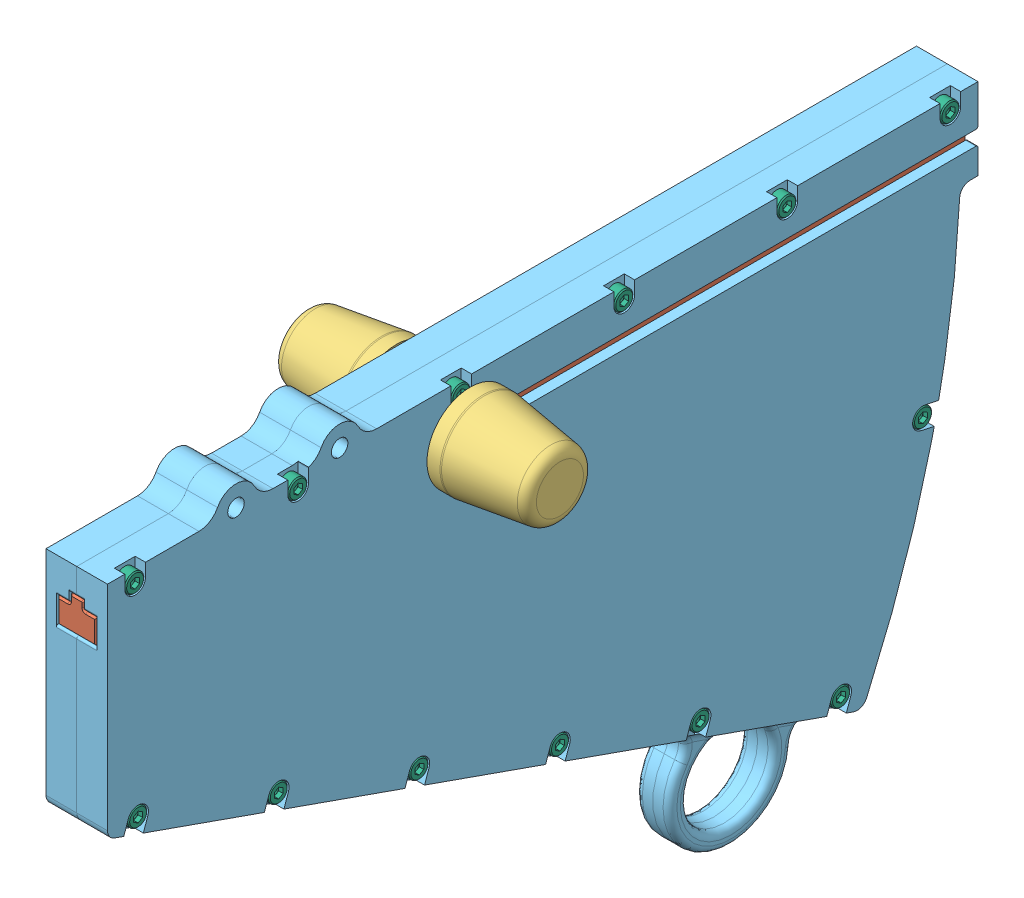
SolidWorks assembly Magazine, configuration Default. Lengths in mm.
Overall size (73.4 166.64 252).
33 component instances, 9 part files, 0 mates.
Components (placement in the parent):
- Follower^Zip Tie Installer-1-1: Follower^Zip Tie Installer-1 [Default] at origin size (14.2 90.09 211.9)
- Pusher Group^Magazine-1: Pusher Group^Magazine [Default] at (0 0 -5.98) size (73.4 25 252) (virtual)
  - Pusher^Zip Tie Installer-1-1: Pusher^Zip Tie Installer-1 [Default] at origin size (11.4 9.7 252)
  - Knob-1-1: Knob-1 [Default] at (10.7 -34.384 -140) x (0 0 -1) z (1 0 0) size (25 25 26)
  - Knob-1-2: Knob-1 [Default] at (-10.7 -34.384 -140) x (0 0 1) z (-1 0 0) size (25 25 26)
  - Dowel Pin 4mm(50mm)-1-1: Dowel Pin 4mm(50mm)-1 [Default] at (0 -34.384 -140) x (0 0 1) z (-1 0 0) size (4 4 50)
- Magazine Casing^Zip Tie Installer-1-1: Magazine Casing^Zip Tie Installer-1 [Default] at origin size (17.8 166.64 252)
- socket head cap screw_am(B18.3.1M - 3 x 0.5 x 10 Hex SHCS -- 10NHX)-1-1: socket head cap screw_am(B18.3.1M - 3 x 0.5 x 10 Hex SHCS -- 10NHX)-1 [Default] at (8.9 -24.334 -239.6) x (-1 0 0) z (0 0 -1) size (13 5.5 5.5)
- socket head cap screw_am(B18.3.1M - 3 x 0.5 x 10 Hex SHCS -- 10NHX)-1-2: socket head cap screw_am(B18.3.1M - 3 x 0.5 x 10 Hex SHCS -- 10NHX)-1 [Default] at (8.9 -24.334 -50.8) x (-1 0 0) z (0 0 -1) size (13 5.5 5.5)
- socket head cap screw_am(B18.3.1M - 3 x 0.5 x 10 Hex SHCS -- 10NHX)-1-3: socket head cap screw_am(B18.3.1M - 3 x 0.5 x 10 Hex SHCS -- 10NHX)-1 [Default] at (8.9 -97.7396 -92.374) x (-1 0 0) z (0 0 -1) size (13 5.5 5.5)
- socket head cap screw_am(B18.3.1M - 3 x 0.5 x 10 Hex SHCS -- 10NHX)-1-4: socket head cap screw_am(B18.3.1M - 3 x 0.5 x 10 Hex SHCS -- 10NHX)-1 [Default] at (8.9 -24.334 -98) x (-1 0 0) z (0 0 -1) size (13 5.5 5.5)
- socket head cap screw_am(B18.3.1M - 3 x 0.5 x 10 Hex SHCS -- 10NHX)-1-5: socket head cap screw_am(B18.3.1M - 3 x 0.5 x 10 Hex SHCS -- 10NHX)-1 [Default] at (8.9 -155.0768 -255.172) x (-1 0 0) z (0 0 -1) size (13 5.5 5.5)
- socket head cap screw_am(B18.3.1M - 3 x 0.5 x 10 Hex SHCS -- 10NHX)-1-6: socket head cap screw_am(B18.3.1M - 3 x 0.5 x 10 Hex SHCS -- 10NHX)-1 [Default] at (8.9 -112.0739 -133.0735) x (-1 0 0) z (0 0 -1) size (13 5.5 5.5)
- socket head cap screw_am(B18.3.1M - 3 x 0.5 x 10 Hex SHCS -- 10NHX)-1-7: socket head cap screw_am(B18.3.1M - 3 x 0.5 x 10 Hex SHCS -- 10NHX)-1 [Default] at (8.9 -24.334 -286.8) x (-1 0 0) z (0 0 -1) size (13 5.5 5.5)
- socket head cap screw_am(B18.3.1M - 3 x 0.5 x 10 Hex SHCS -- 10NHX)-1-8: socket head cap screw_am(B18.3.1M - 3 x 0.5 x 10 Hex SHCS -- 10NHX)-1 [Default] at (8.9 -24.334 -192.4) x (-1 0 0) z (0 0 -1) size (13 5.5 5.5)
- socket head cap screw_am(B18.3.1M - 3 x 0.5 x 10 Hex SHCS -- 10NHX)-1-9: socket head cap screw_am(B18.3.1M - 3 x 0.5 x 10 Hex SHCS -- 10NHX)-1 [Default] at (8.9 -140.7425 -214.4725) x (-1 0 0) z (0 0 -1) size (13 5.5 5.5)
- socket head cap screw_am(B18.3.1M - 3 x 0.5 x 10 Hex SHCS -- 10NHX)-1-10: socket head cap screw_am(B18.3.1M - 3 x 0.5 x 10 Hex SHCS -- 10NHX)-1 [Default] at (8.9 -126.4082 -173.773) x (-1 0 0) z (0 0 -1) size (13 5.5 5.5)
- socket head cap screw_am(B18.3.1M - 3 x 0.5 x 10 Hex SHCS -- 10NHX)-1-11: socket head cap screw_am(B18.3.1M - 3 x 0.5 x 10 Hex SHCS -- 10NHX)-1 [Default] at (8.9 -83.4053 -51.6745) x (-1 0 0) z (0 0 -1) size (13 5.5 5.5)
- socket head cap screw_am(B18.3.1M - 3 x 0.5 x 10 Hex SHCS -- 10NHX)-1-12: socket head cap screw_am(B18.3.1M - 3 x 0.5 x 10 Hex SHCS -- 10NHX)-1 [Default] at (8.9 -24.334 -145.2) x (-1 0 0) z (0 0 -1) size (13 5.5 5.5)
- socket head cap screw_am(B18.3.1M - 3 x 0.5 x 10 Hex SHCS -- 10NHX)-1-13: socket head cap screw_am(B18.3.1M - 3 x 0.5 x 10 Hex SHCS -- 10NHX)-1 [Default] at (8.9 -96.9035 -278.8752) x (-1 0 0) z (0 0 -1) size (13 5.5 5.5)
- Compression Spring 10mm-1-1: Compression Spring 10mm-1 [Default] at (0 -56.02 -53.984) size (6.82 12.35 6.82)
- Rectangular Spring-1-1: Rectangular Spring-1 [Default] at (0 -101.0153 -160.6758) x (0 -0.332197 -0.94321) z (-1 0 0) size (180.85 16.04 8.85)
- 94180A331_HEAT-SET INSERTS FOR PLASTICS-1-1: 94180A331_HEAT-SET INSERTS FOR PLASTICS-1 [Default] at (0 -96.9035 -278.8752) x (0 -1 0) z (0 0 1) size (5.56 4.12 5.56)
- 94180A331_HEAT-SET INSERTS FOR PLASTICS-1-2: 94180A331_HEAT-SET INSERTS FOR PLASTICS-1 [Default] at (0 -24.334 -98) x (0 -1 0) z (0 0 1) size (5.56 4.12 5.56)
- 94180A331_HEAT-SET INSERTS FOR PLASTICS-1-3: 94180A331_HEAT-SET INSERTS FOR PLASTICS-1 [Default] at (0 -24.334 -286.8) x (0 -1 0) z (0 0 1) size (5.56 4.12 5.56)
- 94180A331_HEAT-SET INSERTS FOR PLASTICS-1-4: 94180A331_HEAT-SET INSERTS FOR PLASTICS-1 [Default] at (0 -24.334 -145.2) x (0 -1 0) z (0 0 1) size (5.56 4.12 5.56)
- 94180A331_HEAT-SET INSERTS FOR PLASTICS-1-5: 94180A331_HEAT-SET INSERTS FOR PLASTICS-1 [Default] at (0 -126.4082 -173.773) x (0 -1 0) z (0 0 1) size (5.56 4.12 5.56)
- 94180A331_HEAT-SET INSERTS FOR PLASTICS-1-6: 94180A331_HEAT-SET INSERTS FOR PLASTICS-1 [Default] at (0 -97.7396 -92.374) x (0 -1 0) z (0 0 1) size (5.56 4.12 5.56)
- 94180A331_HEAT-SET INSERTS FOR PLASTICS-1-7: 94180A331_HEAT-SET INSERTS FOR PLASTICS-1 [Default] at (0 -24.334 -239.6) x (0 -1 0) z (0 0 1) size (5.56 4.12 5.56)
- 94180A331_HEAT-SET INSERTS FOR PLASTICS-1-8: 94180A331_HEAT-SET INSERTS FOR PLASTICS-1 [Default] at (0 -140.7425 -214.4725) x (0 -1 0) z (0 0 1) size (5.56 4.12 5.56)
- 94180A331_HEAT-SET INSERTS FOR PLASTICS-1-9: 94180A331_HEAT-SET INSERTS FOR PLASTICS-1 [Default] at (0 -24.334 -192.4) x (0 -1 0) z (0 0 1) size (5.56 4.12 5.56)
- 94180A331_HEAT-SET INSERTS FOR PLASTICS-1-10: 94180A331_HEAT-SET INSERTS FOR PLASTICS-1 [Default] at (0 -112.0739 -133.0735) x (0 -1 0) z (0 0 1) size (5.56 4.12 5.56)
- 94180A331_HEAT-SET INSERTS FOR PLASTICS-1-11: 94180A331_HEAT-SET INSERTS FOR PLASTICS-1 [Default] at (0 -155.0768 -255.172) x (0 -1 0) z (0 0 1) size (5.56 4.12 5.56)
